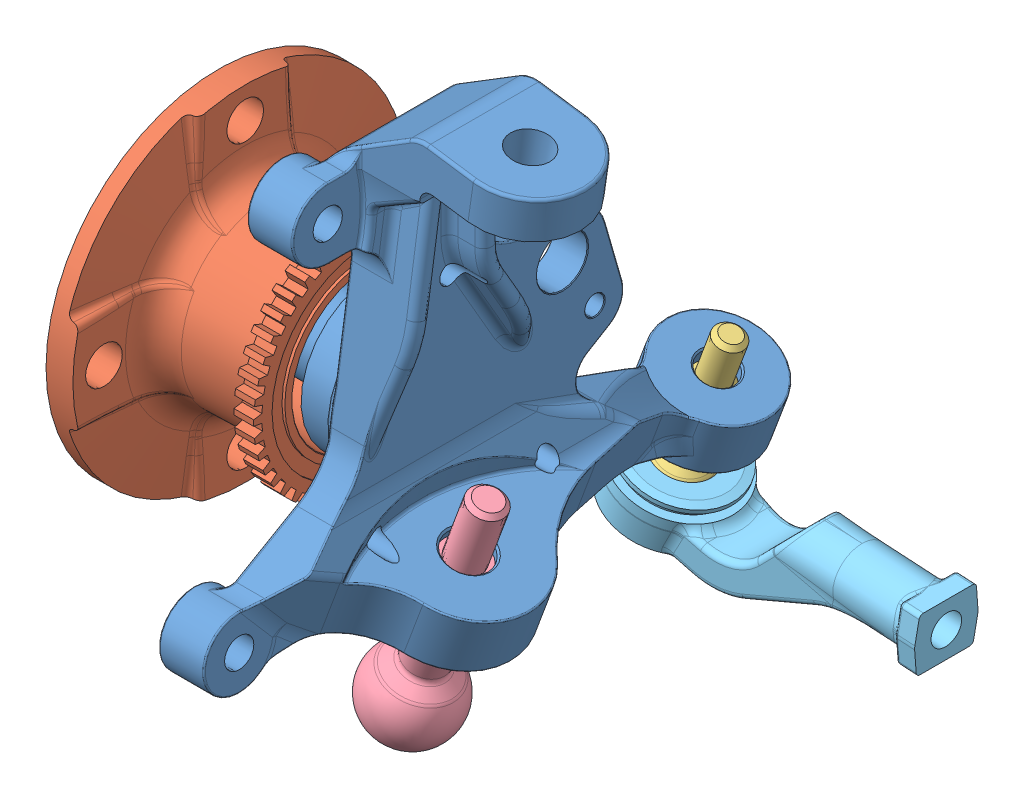
SolidWorks assembly Mazda MX5 Miata front upright_1, configuration Default. Lengths in mm.
Overall size (155.22 209.53 200.12).
11 component instances, 6 part files, 0 mates.
Components (placement in the parent):
- CL_9031-1000-1: CL_9031-1000 [Default] at origin size (155.22 194.39 200.12)
  - CL_9031-1001-1: CL_9031-1001 [Default] at origin size (155.22 167.17 200.12)
  - CL_9031-3001-1: CL_9031-3001 [Default] at origin size (67.25 122 122)
  - CL_8027-4002-1: CL_8027-4002 [Default] at (65.3564 -77.401 -97.2163) x (-0.937282 0.348572 0) z (0 0 1) size (21 64.7 21)
- CL_8027-2000-1: CL_8027-2000 [Default] at (77.4695 -86.7603 8.8272) x (0.937282 -0.348572 0) z (0 0 1) size (30 92.5 30)
  - CL_8027-2002-1: CL_8027-2002 [Default] x (-1 0 0) z (0 0 1) size (30 92.5 30)
- CL_8027-4000-1: CL_8027-4000 [Default] at (65.3564 -77.401 -97.2163) x (0.937282 -0.348572 0) z (0 0 1) size (112.33 70.7 39.5) (hidden)
  - CL_8027-4001-1: CL_8027-4001 [Default] at origin size (112.33 57.26 39.5)
    - CL_8027-4001-1: CL_8027-4001 [Default] at origin size (112.33 54.26 39.5)
    - CL_8027-4001_1-1: CL_8027-4001_1 [Default] at origin size (21.5 3.5 21.5)
  - CL_8027-4002-1: CL_8027-4002 [Default] x (-1 0 0) z (0 0 1) size (21 64.7 21)
